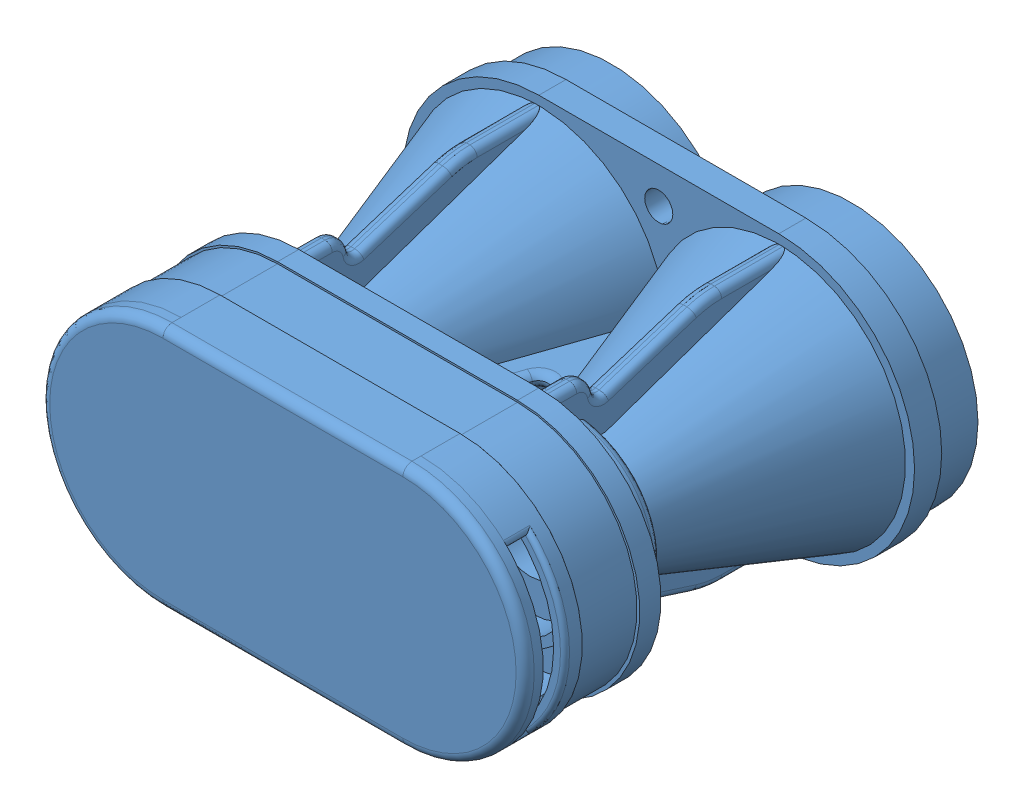
SolidWorks assembly laser_rangefinder, configuration Default. Lengths in mm.
Overall size (56.5 30 49.5).
3 component instances, 2 part files, 2 mates.
Components (placement in the parent):
- laser_rangefinder_body-1: laser_rangefinder_body [Default] at (-96.1946 -111.9998 299.4797) size (56.5 30 49.5)
- lens-1: lens [Default] at (36.3054 23.0002 26.9797) x (0 0 -1) z (1 0 0) size (2.27 25 25)
- lens-3: lens [Default] at (9.8054 23.0002 26.9797) x (0 0 -1) z (1 0 0) size (2.27 25 25)
Mates (geometry in assembly coordinates):
- Coincident2: coincident anti-aligned: circle of laser_rangefinder_body-1; circle of lens-1
- Coincident3: coincident anti-aligned: circle of laser_rangefinder_body-1; circle of lens-3
